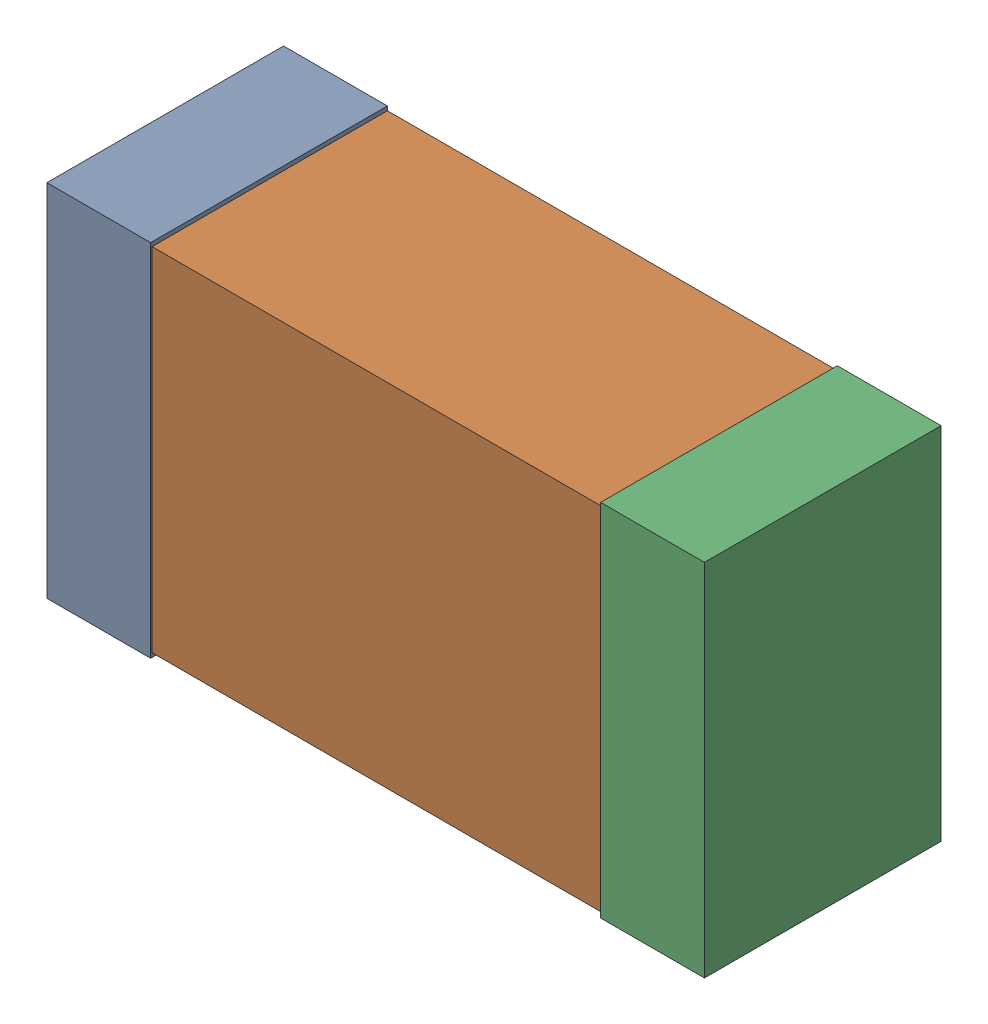
SolidWorks assembly C13_Motor_11Kanaloa_v2.0.0_Motor, configuration Default. Lengths in mm.
Overall size (2.38 1.3 0.85).
6 component instances, 2 part files, 0 mates.
Components (placement in the parent):
- 352877648-1: 352877648 [Default] at (145.05 170.434 0) size (0.38 1.3 0.85)
  - Extruded_14-1: Extruded_14 [Default] at origin size (0.38 1.3 0.85)
- 352877392-1: 352877392 [Default] at (146.05 170.434 0) size (2.2 1.27 0.85)
  - Extruded_15-1: Extruded_15 [Default] at origin size (2.2 1.27 0.85)
- 352877648-2: 352877648 [Default] at (147.05 170.434 0) size (0.38 1.3 0.85)
  - Extruded_14-1: Extruded_14 [Default] at origin size (0.38 1.3 0.85)
